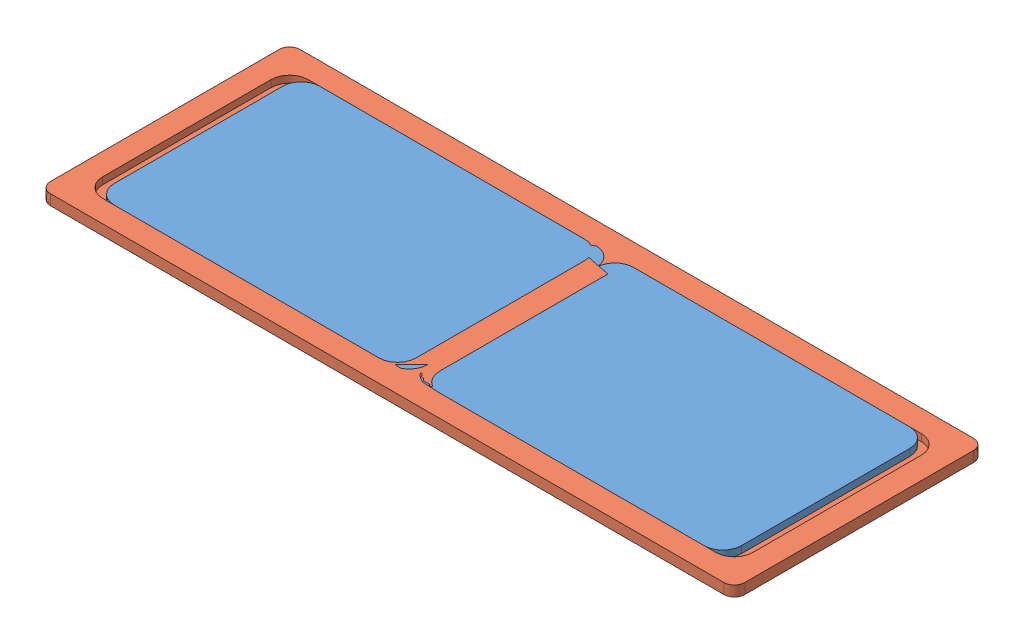
SolidWorks assembly shell_rect_assembly, configuration Default. Lengths in mm.
Overall size (538.7 124 226.75).
13 component instances, 6 part files, 10 mates.
Components (placement in the parent):
- rear_plate_assembly-1: rear_plate_assembly [Default] at origin size (19 115 197.4)
  - front_window_large-1: front_window_large [Default] at (-269.35 -19.485 0) x (0 0 -1) z (1 0 0) size (68 107 6)
  - front_window_large-2: front_window_large [Default] at (-269.35 -19.485 -121.4) x (0 0 -1) z (1 0 0) size (68 107 6)
  - rear_plate-1: rear_plate [Default] at (-260.35 -19.485 0) x (0 0 1) z (-1 0 0) size (197.4 115 19)
- front_plate_assembly-1: front_plate_assembly [Default] at origin size (19 111 197.4)
  - front_plate-1: front_plate [Default] at (260.35 0 0) x (0 0 -1) z (1 0 0) size (197.4 85.21 16)
  - front_window_single-1: front_window_single [Default] at (263.35 0 0) x (0 0 -1) z (1 0 0) size (78 111 6)
- side_wall_assembly-1: side_wall_assembly [Default] at origin (suppressed, hidden)
- lid_assembly-1: lid_assembly [Default] at origin size (538.7 9 215.4)
  - Lid_window-1: Lid_window [Default] at (0 60.5 -98.7) x (-1 0 0) z (0 1 0) size (225.62 177.4 6)
  - lid_rectangular-1: lid_rectangular [Default] at (0 66.5 -98.7) x (1 0 0) z (0 -1 0) size (538.7 215.4 9)
  - Lid_window-2: Lid_window [Default] at (0 66.5 -98.7) x (1 0 0) z (0 -1 0) size (225.62 177.4 6)
- side_wall_assembly-2: side_wall_assembly [Default] x (-1 0 0) z (0 0 -1) (suppressed, hidden)
Mates (geometry in assembly coordinates):
- Coincident151: coincident aligned: plane of side_wall_assembly-1/side_plate-1 through (260.35 57.5 -107.7) normal (0 1 0); plane of rear_plate_assembly-1/rear_plate-1 through (-269.35 57.5 -98.7) normal (0 1 0)
- Coincident152: coincident aligned: plane of side_wall_assembly-1/side_plate-1 through (260.35 57.5 -107.7) normal (0 1 0); plane of front_plate_assembly-1/rear_plate-1 through (269.35 57.5 98.7) normal (0 1 0)
- Coincident143: coincident aligned: plane of rear_plate_assembly-1/rear_plate-1 through (-269.35 -19.485 0) normal (-1 0 0); plane of lid_assembly-1/lid_rectangular-1 through (-269.35 57.5 -97.7) normal (-1 0 0)
- Coincident157: coincident anti-aligned: line of rear_plate_assembly-1/rear_plate-1 through (-260.35 47.5 -98.7) axis (0 -1 0); line of side_wall_assembly-1/side_plate-1 through (-260.35 -57.5 -98.7) axis (0 1 0)
- Coincident168: coincident anti-aligned: plane of rear_plate_assembly-1/rear_plate-1 through (-269.35 57.5 98.7) normal (0 0 1); plane of side_wall_assembly-2/side_plate-1 through (0 -42.5 98.7) normal (0 0 -1)
- Coincident169: coincident anti-aligned: line of rear_plate_assembly-1/rear_plate-1 through (-260.35 -57.5 98.7) axis (0 1 0); line of side_wall_assembly-2/side_plate-1 through (-260.35 47.5 98.7) axis (0 -1 0)
- Coincident170: coincident aligned: plane of rear_plate_assembly-1/rear_plate-1 through (-269.35 -57.5 98.7) normal (0 -1 0); plane of side_wall_assembly-2/side_plate-1 through (-260.35 -57.5 107.7) normal (0 -1 0)
- Coincident158: coincident anti-aligned: line of front_plate_assembly-1/rear_plate-1 through (260.35 -57.5 -98.7) axis (0 1 0); line of side_wall_assembly-1/side_plate-1 through (260.35 47.5 -98.7) axis (0 -1 0)
- Coincident155: coincident anti-aligned: plane of side_wall_assembly-1/side_plate-1 through (260.35 57.5 -107.7) normal (0 1 0); plane of lid_assembly-1/lid_rectangular-1 through (259.35 57.5 97.7) normal (0 -1 0)
- Coincident156: coincident aligned: plane of side_wall_assembly-1/side_plate-1 through (0 -42.5 -107.7) normal (0 0 -1); plane of lid_assembly-1/lid_rectangular-1 through (259.35 57.5 -107.7) normal (0 0 -1)
